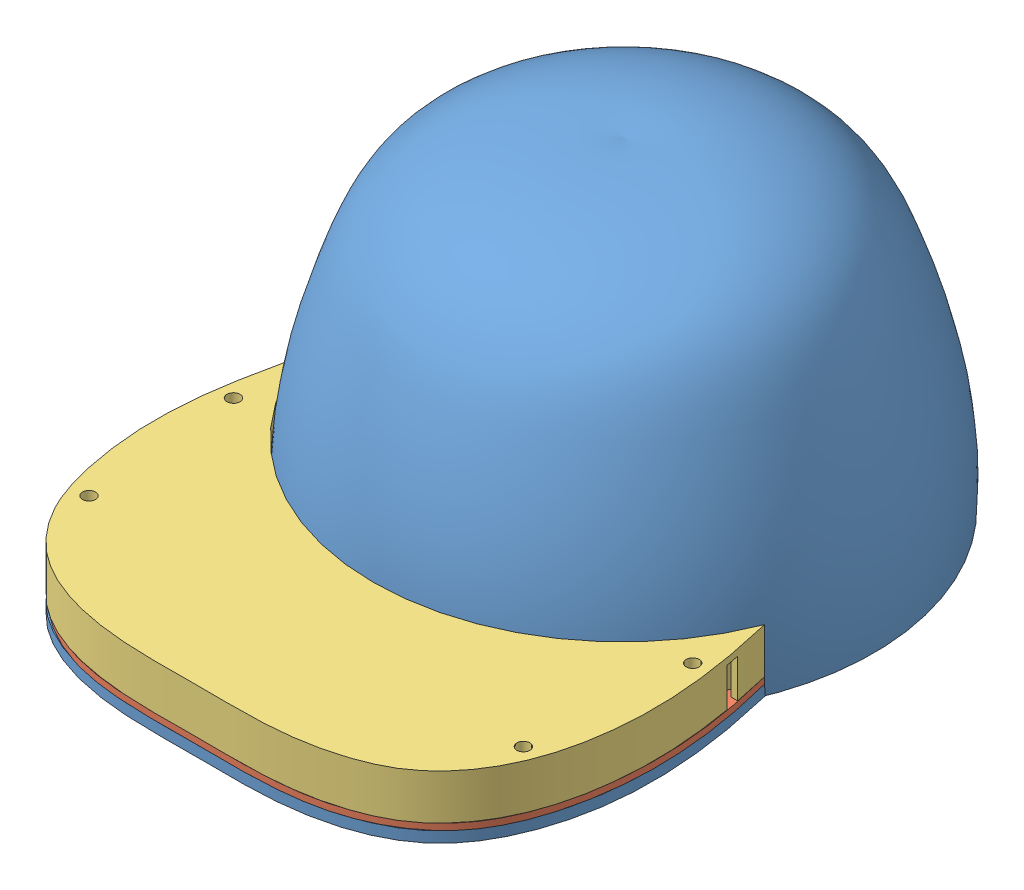
SolidWorks assembly SmartHat, configuration Default. Lengths in mm.
Overall size (598.31 133.11 548.15).
3 component instances, 3 part files, 6 mates.
Components (placement in the parent):
- Snapback-1: Snapback [Default] at (34.4991 42.3964 303.671) size (555.36 133.11 548.15)
- ElectronicsBrimMount-2: ElectronicsBrimMount [Default] at (18.5954 49.0764 293.3836) x (-0.837169 0 -0.546944) z (-0.546944 0 0.837169) size (204.89 11.39 186.5)
- ElectronicsCover-3: ElectronicsCover [Default] at (34.377 46.6164 269.3005) x (-0.837169 0 -0.546944) z (-0.546944 0 0.837169) size (215.32 22.5 199.42)
Mates (geometry in assembly coordinates):
- Coincident6: coincident anti-aligned: plane of Snapback-1 through (34.4991 46.5764 303.671) normal (0 1 0); plane of ElectronicsBrimMount-2 through (34.4991 46.5764 269.041) normal (0 -1 0)
- Coincident7: coincident: point of Snapback-1; point of ElectronicsBrimMount-2
- Coincident8: coincident: point of Snapback-1; point of ElectronicsBrimMount-2
- Coincident9: coincident anti-aligned: plane of ElectronicsBrimMount-2 through (34.4991 49.0764 269.041) normal (0 1 0); plane of ElectronicsCover-3 through (34.4149 49.0764 303.6711) normal (0 -1 0)
- Coincident10: coincident: point of ElectronicsBrimMount-2; point of ElectronicsCover-3
- Coincident11: coincident: point of ElectronicsBrimMount-2; point of ElectronicsCover-3
